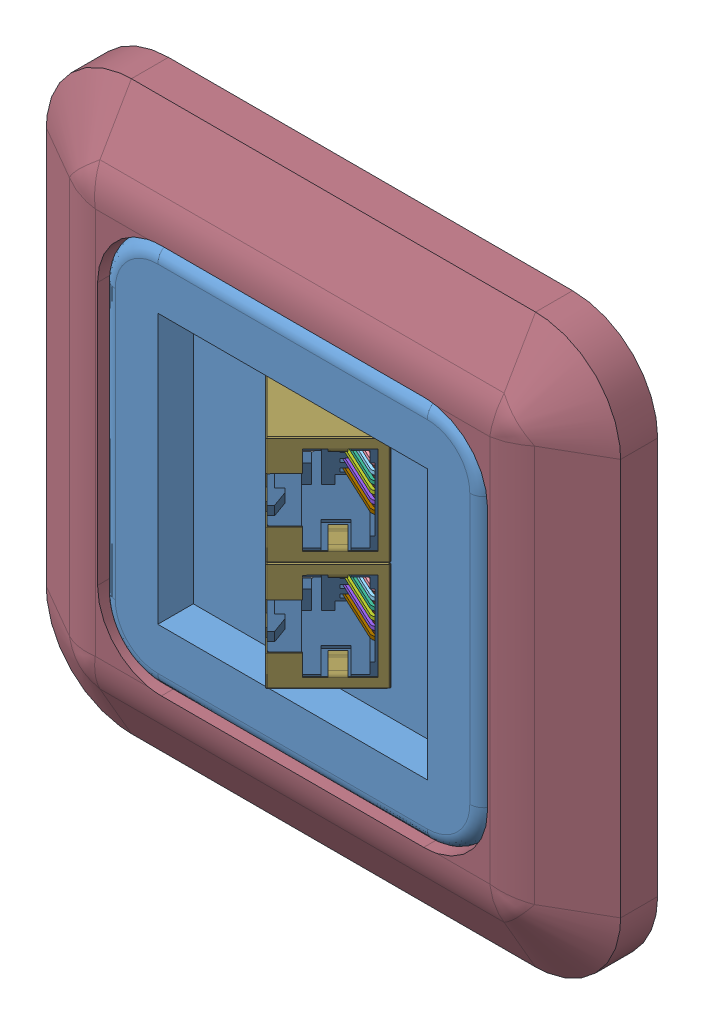
SolidWorks assembly Steckdose_1er-RJ, configuration Standard. Lengths in mm.
Overall size (81 80 25.23).
27 component instances, 13 part files, 3 mates.
Components (placement in the parent):
- Steckdose-RJ45-1: Steckdose-RJ45 [Standard] at (18.9082 -0.7233 10.2377) size (54 54 25.23)
  - Buchse-RJ45-1: Buchse-RJ45 [Standard] at (-88.9836 -48.9043 64.0274) size (54 54 6)
  - 65864-1: 65864 [Default] at (-11.8405 9.7148 53.1274) size (17.49 15.42 25.23)
    - 65864_01-1: 65864_01 [Default] at origin size (9.69 0.75 13.83)
    - 65864_02-1: 65864_02 [Default] at origin size (9.44 0.68 13.83)
    - 65864_03-1: 65864_03 [Default] at origin size (9.69 0.61 13.84)
    - 65864_04-1: 65864_04 [Default] at origin size (9.44 0.54 13.83)
    - 65864_05-1: 65864_05 [Default] at origin size (9.69 0.54 13.82)
    - 65864_06-1: 65864_06 [Default] at origin size (9.44 0.6 13.83)
    - 65864_07-1: 65864_07 [Default] at origin size (9.69 0.68 13.83)
    - 65864_08-1: 65864_08 [Default] at origin size (9.44 0.75 13.83)
    - 65864_09-1: 65864_09 [Default] at origin size (17.11 15.1 23.65)
    - 65864_10-1: 65864_10 [Default] at origin size (6.36 10.31 6.36)
    - 65864_11-1: 65864_11 [Default] at origin size (17.49 15.42 25.23)
  - 65864-2: 65864 [Default] at (-11.8405 -5.6852 53.1274) size (17.49 15.42 25.23)
    - 65864_01-1: 65864_01 [Default] at origin size (9.69 0.75 13.83)
    - 65864_02-1: 65864_02 [Default] at origin size (9.44 0.68 13.83)
    - 65864_03-1: 65864_03 [Default] at origin size (9.69 0.61 13.84)
    - 65864_04-1: 65864_04 [Default] at origin size (9.44 0.54 13.83)
    - 65864_05-1: 65864_05 [Default] at origin size (9.69 0.54 13.82)
    - 65864_06-1: 65864_06 [Default] at origin size (9.44 0.6 13.83)
    - 65864_07-1: 65864_07 [Default] at origin size (9.69 0.68 13.83)
    - 65864_08-1: 65864_08 [Default] at origin size (9.44 0.75 13.83)
    - 65864_09-1: 65864_09 [Default] at origin size (17.11 15.1 23.65)
    - 65864_10-1: 65864_10 [Default] at origin size (6.36 10.31 6.36)
    - 65864_11-1: 65864_11 [Default] at origin size (17.49 15.42 25.23)
- Wandplatte_1er-1: Wandplatte_1er [Standard] at (0.9246 -49.6276 74.2651) size (81 80 11.01)
Mates (geometry in assembly coordinates):
- Deckungsgleich1: coincident: plane of Steckdose-RJ45-1/Buchse-RJ45-1 through (-12.0773 -17.7085 68.2651) normal (0 0 -1); plane of Wandplatte_1er-1 through (-11.5773 -17.2085 68.2651) normal (0 0 1)
- Abstand1: distance = 0.5 mm: plane of Wandplatte_1er-1 through (-11.5773 -26.2085 68.2651) normal (0 1 0); plane of Steckdose-RJ45-1/Buchse-RJ45-1 through (-12.0773 -25.7085 68.2651) normal (0 -1 0)
- Abstand2: distance = 0.5 mm anti-aligned: plane of Wandplatte_1er-1 through (34.4227 -17.2085 68.2651) normal (-1 0 0); plane of Steckdose-RJ45-1/Buchse-RJ45-1 through (33.9227 20.2915 68.2651) normal (1 0 0)
